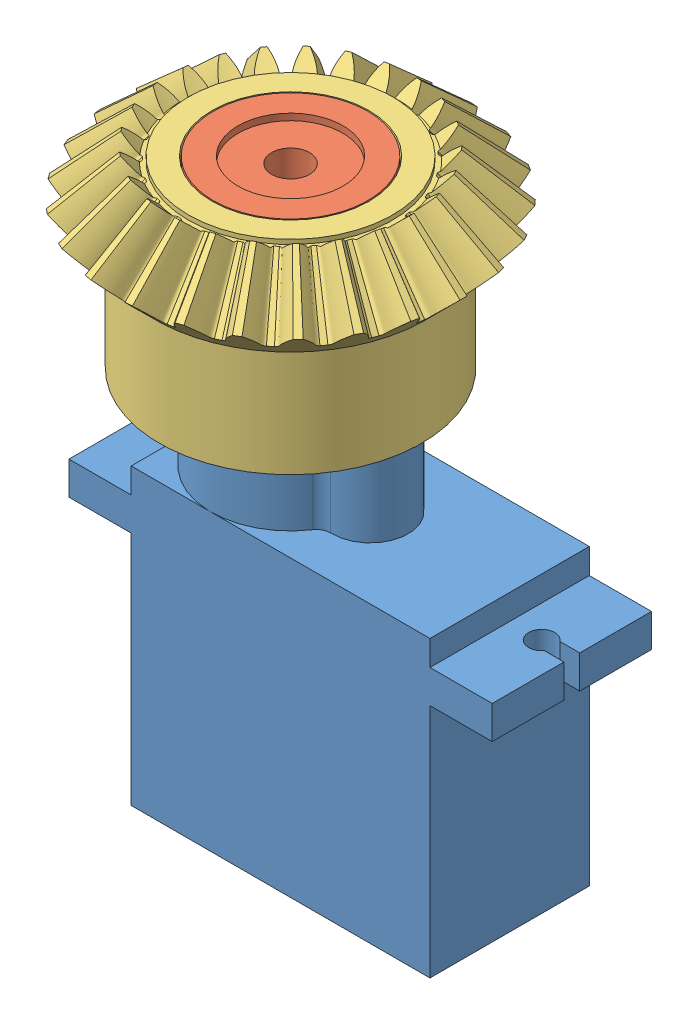
SolidWorks assembly servo&gear, configuration 默认. Lengths in mm.
Overall size (34.67 43.75 26.51).
3 component instances, 3 part files, 5 mates.
Components (placement in the parent):
- servo_motor(MG90D)-1: servo_motor(MG90D) [默认] at origin size (32.3 32.83 12.16)
- servo&gear_connector-1: servo&gear_connector [默认] at (-5.32 28.93 0) size (12 14 12)
- bevel_gear_25x1x12-1: bevel_gear_25x1x12 [默认] at (-5.32 26.93 0) x (0 1 0) z (0 0 1) size (14.82 26.47 26.51)
Mates (geometry in assembly coordinates):
- 同心1: concentric aligned: cylinder of servo&gear_connector-1 through (-5.32 42.93 0) axis (0 -1 0) radius 5.9; cylinder of bevel_gear_25x1x12-1 through (-5.32 28.93 0) axis (0 -1 0) radius 6
- 同心3: concentric aligned: cylinder of servo_motor(MG90D)-1 through (-5.32 32.83 0) axis (0 -1 0) radius 2.3; cylinder of servo&gear_connector-1 through (-5.32 32.83 0) axis (0 -1 0) radius 2.3
- 重合4: coincident anti-aligned: plane of servo_motor(MG90D)-1 through (-5.32 32.83 0) normal (0 1 0); plane of servo&gear_connector-1 through (-5.32 32.83 0) normal (0 -1 0)
- 重合6: coincident aligned: plane of servo&gear_connector-1 through (-5.32 42.93 0) normal (0 1 0); plane of bevel_gear_25x1x12-1 through (-5.32 42.93 0) normal (0 1 0)
- 重合7: coincident aligned: plane of servo&gear_connector-1 through (-5.32 28.93 0) normal (0 0 1); plane of bevel_gear_25x1x12-1 through (-5.32 26.93 0) normal (0 0 1)
